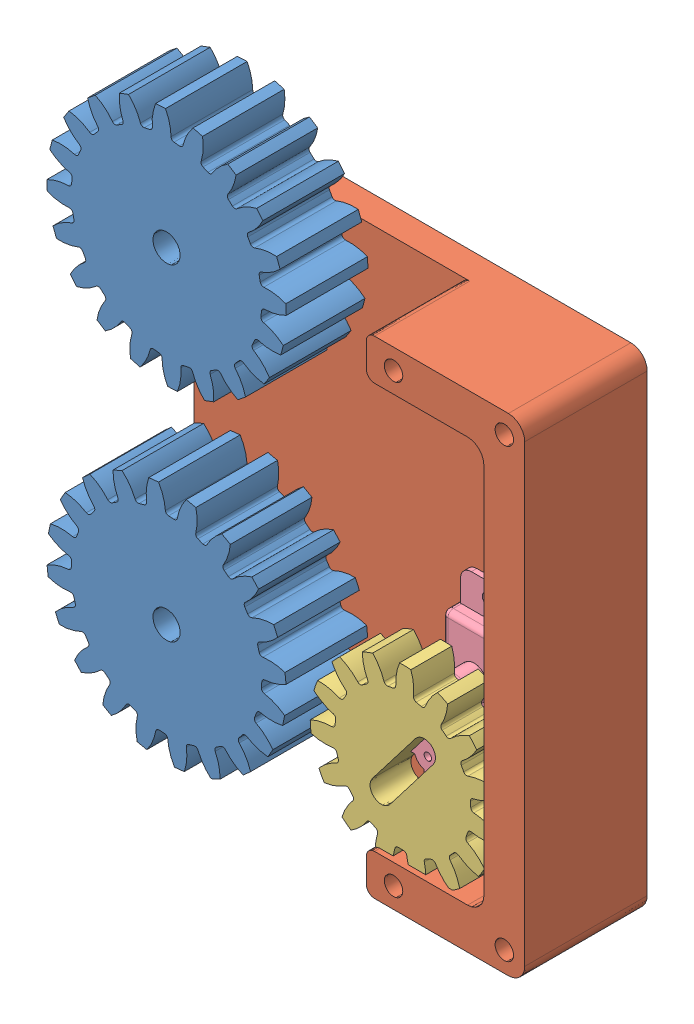
SolidWorks assembly Gear Assembly, configuration Default. Lengths in mm.
Overall size (105.31 119.17 34).
6 component instances, 5 part files, 11 mates.
Components (placement in the parent):
- Driven_Gears-1: Driven_Gears [Default] at (-29.2 -30 12.5) x (0.547302 -0.836935 0) z (0 0 1) size (43.7 43.7 15)
- Driven_Gears-2: Driven_Gears [Default] at (-29.2 30 12.5) x (-0.408931 -0.912565 0) z (0 0 1) size (43.7 43.7 15)
- Servo_Mount-1: Servo_Mount [Default] at origin size (78.3 89.47 22.5)
- Driving_Gears-1: Driving_Gears [Default] at (15.7127 -30.1409 17.7696) x (0.792874 -0.609385 0) z (0 0 1) size (43 43 7.5)
- Szervo HS55-1: Szervo HS55 [Default] at (15.8 -24.97 -11.5) x (0 -1 0) z (-1 0 0) size (34.8 28.5 15.5)
- Servo_Mount_B-1: Servo_Mount_B [Default] at (-12.5 10 22.5) size (58.3 79.47 5) (hidden)
Mates (geometry in assembly coordinates):
- Coincident7: coincident aligned: plane of Driven_Gears-1 through (-29.2 -30 20) normal (0 0 1); plane of Driven_Gears-2 through (-29.2 30 20) normal (0 0 1)
- Coincident10: coordinate: point of Servo_Mount-1; point of assembly
- Concentric3: concentric anti-aligned: cylinder of Driven_Gears-1 through (-29.2 -30 5) axis (0 0 1) radius 2.5; cylinder of Servo_Mount-1 through (-29.2 -30 0) axis (0 0 -1) radius 2.5
- Concentric4: concentric anti-aligned: cylinder of Driven_Gears-2 through (-29.2 30 5) axis (0 0 1) radius 2.5; cylinder of Servo_Mount-1 through (-29.2 30 0) axis (0 0 -1) radius 2.5
- Coincident11: coincident anti-aligned: plane of Driven_Gears-1 through (-29.2 -30 5) normal (0 0 -1); plane of Servo_Mount-1 through (0 0 5) normal (0 0 1)
- GearMate2: gear = 5 : 5 mm: cylinder of Driven_Gears-2 through (-29.2 30 5) axis (0 0 1) radius 2.5; cylinder of Driven_Gears-1 through (-29.2 -30 5) axis (0 0 1) radius 2.5
- Concentric6: concentric anti-aligned: circle of Szervo HS55-1; cylinder of Servo_Mount-1 through (15.8 -39.47 5) axis (0 0 1) radius 1.45
- Coincident12: coincident anti-aligned: plane of Servo_Mount-1 through (0 0 5) normal (0 0 1); plane of Szervo HS55-1 through (10.8 -36.37 5) normal (0 0 -1)
- Concentric7: concentric anti-aligned: circle of Szervo HS55-1; cylinder of Servo_Mount-1 through (15.8 -10.47 5) axis (0 0 1) radius 1.45
- Concentric10: concentric anti-aligned: cylinder of Driven_Gears-2 through (-29.2 30 5) axis (0 0 1) radius 2.5; cylinder of Servo_Mount_B-1 through (-29.2 30 22.5) axis (0 0 -1) radius 2.5
- Coincident16: coincident anti-aligned: plane of Servo_Mount-1 through (0 0 22.5) normal (0 0 1); plane of Servo_Mount_B-1 through (-12.5 10 22.5) normal (0 0 -1)
